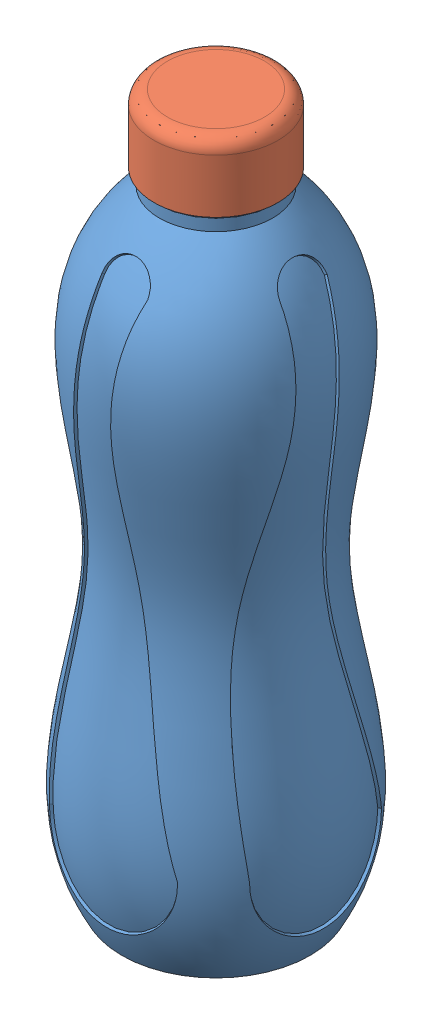
SolidWorks assembly Assem2, configuration Default. Lengths in mm.
Overall size (116.86 261 116.86).
2 component instances, 2 part files, 3 mates.
Components (placement in the parent):
- WAter bottle-1: WAter bottle [Default] at origin size (116.86 260 116.86)
- cap-1: cap [Default] at (0 121 0) x (-0.324798 0 -0.945783) z (0.945783 0 -0.324798) size (54.98 25 48.5)
Mates (geometry in assembly coordinates):
- Coincident1: coordinate: point of WAter bottle-1; point of assembly
- Concentric1: concentric aligned: cylinder of WAter bottle-1 through (0 145 0) axis (0 -1 0) radius 21; cylinder of cap-1 through (0 121 0) axis (0 -1 0) radius 21
- Coincident2: coincident anti-aligned: plane of WAter bottle-1 through (0 121 21) normal (0 1 0); plane of cap-1 through (-7.4704 121 -21.753) normal (0 -1 0)
